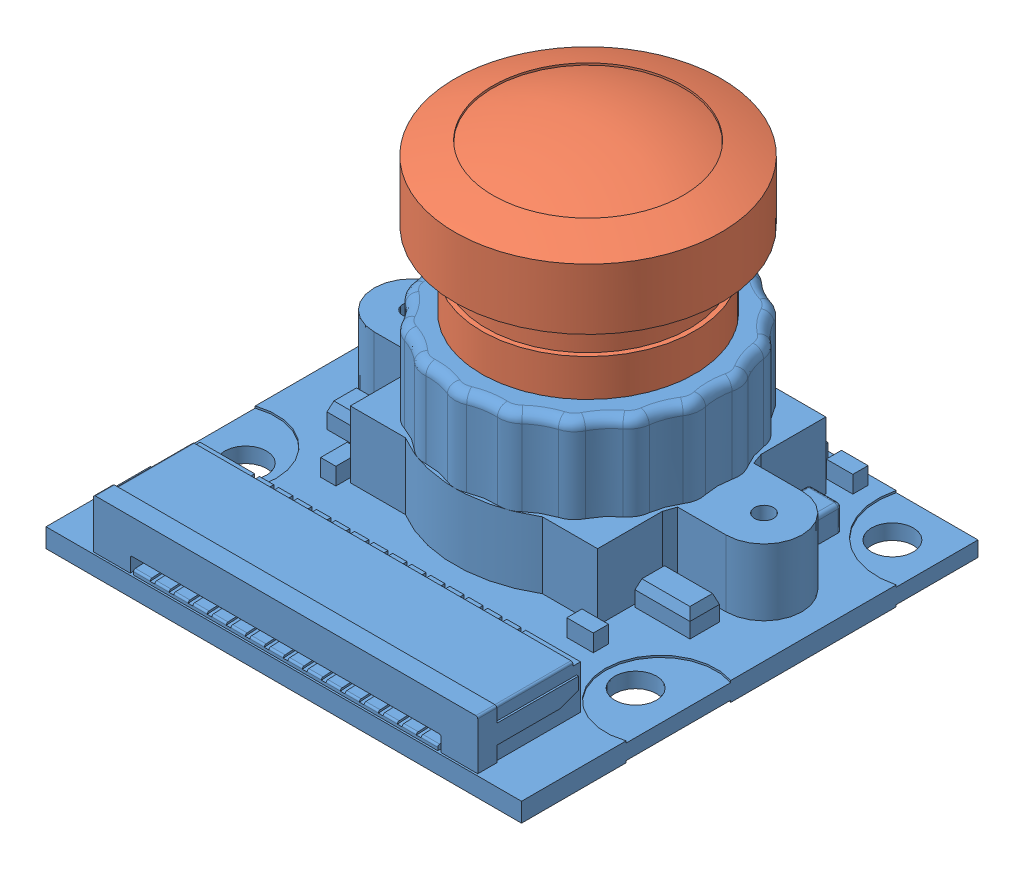
SolidWorks assembly rpiCameraMAssembly1, configuration Varsayılan. Lengths in mm.
Overall size (25 19.16 24).
2 component instances, 2 part files, 0 mates.
Components (placement in the parent):
- rpiCameraM_1-1: rpiCameraM_1 [Varsayılan] at origin size (25 10.51 24)
- rpiCameraM_lens_1-1: rpiCameraM_lens_1 [Varsayılan] at (0 3.9538 -4) x (-0.999681 0 0.025248) z (-0.025248 0 -0.999681) size (14 13.7 14)
